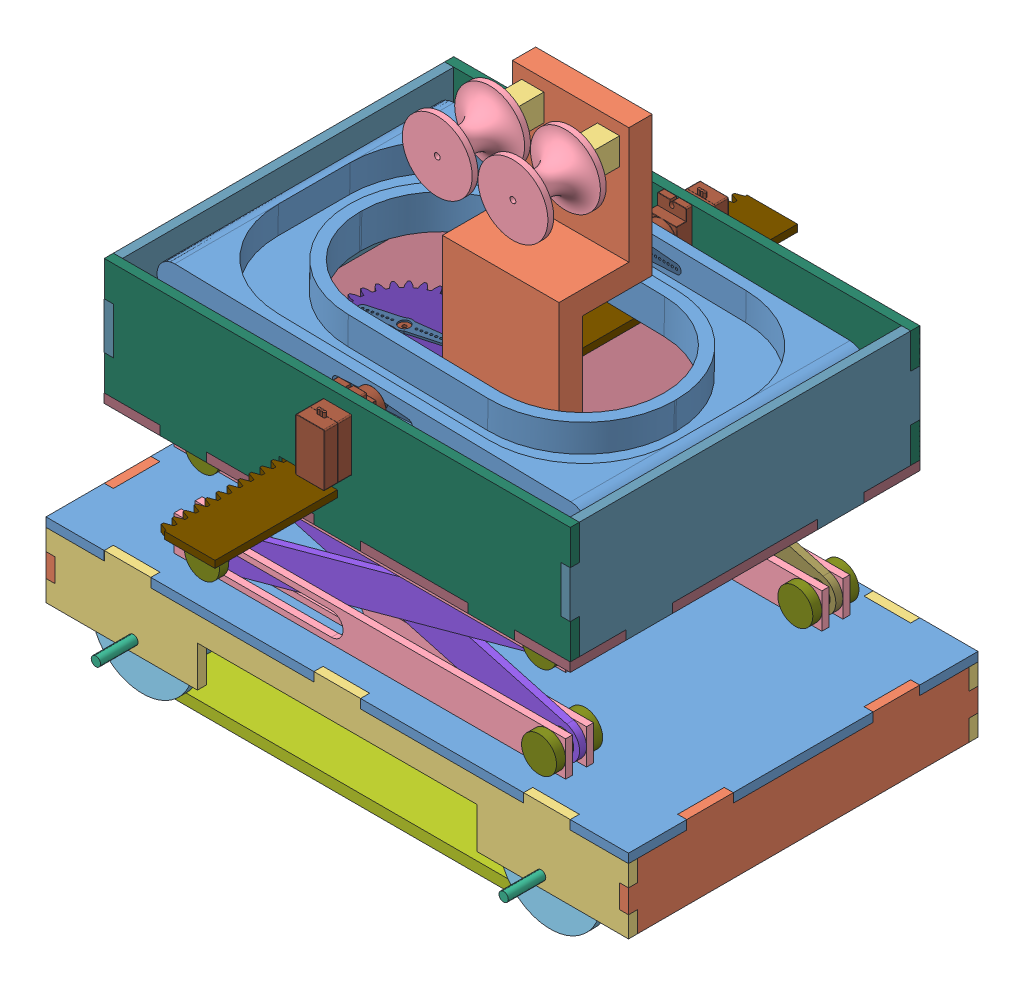
SolidWorks assembly Robot Assembly, configuration Default. Lengths in mm.
Overall size (250 228.82 250).
57 component instances, 22 part files, 82 mates.
Components (placement in the parent):
- Baseplate Assembly-1: Baseplate Assembly [Default] at (17.3063 15.6538 -16.3703) size (250 46.9 150)
  - Baseplate-1: Baseplate [Default] at (65.4966 128.7181 206.065) size (250 3.9 150)
  - Baseplate Short Side-1: Baseplate Short Side [Default] at (186.5966 114.7181 206.065) x (0 0 -1) z (0 -1 0) size (150 3.9 31.9)
  - Baseplate Wide Side-1: Baseplate Wide Side [Default] at (65.4966 114.7181 281.065) x (-1 0 0) z (0 -1 0) size (250 3.9 31.9)
  - Lift Axle Track-1: Lift Axle Track [Default] at (149.4966 132.6181 267.065) x (-1 0 0) z (0 -1 0) size (168 3 18.9)
  - Baseplate Short Side-2: Baseplate Short Side [Default] at (-55.6034 114.7181 206.065) x (0 0 1) z (0 -1 0) size (150 3.9 31.9)
  - Baseplate Wide Side-2: Baseplate Wide Side [Default] at (65.4966 114.7181 134.965) x (-1 0 0) z (0 -1 0) size (250 3.9 31.9)
  - Lift Axle Track-2: Lift Axle Track [Default] at (149.4966 132.6181 157.065) x (-1 0 0) z (0 -1 0) size (168 3 18.9)
  - Lift Axle Track-3: Lift Axle Track [Default] at (149.4966 132.6181 258.065) x (-1 0 0) z (0 -1 0) size (168 3 18.9)
  - Lift Axle Track-4: Lift Axle Track [Default] at (149.4966 132.6181 148.065) x (-1 0 0) z (0 -1 0) size (168 3 18.9)
- Wheel Assembly-4: Wheel Assembly [Default] at (-9.3855 251.3291 -27.7634) x (-1 0 0) z (0 0 1) size (227.01 52.01 182.2)
  - Wheel-1: Wheel [Default] at (-179.6884 129.9573 230.5581) x (0 0 -1) z (0.97923 0.202752 0) size (58 44 44)
  - Wheel-2: Wheel [Default] at (-179.6884 129.9573 146.3581) x (0 0 -1) z (1 0 0) size (58 44 44)
  - Wheel Axle-4: Wheel Axle [Default] at (-179.6884 129.9573 126.3581) size (4 4 182.2)
  - Treads-1: Treads [Default] at (-92.1884 129.9573 234.1581) size (216.4 41.4 50.8)
  - Treads-2: Treads [Default] at (-92.1884 129.9573 149.9581) size (216.4 41.4 50.8)
  - Wheel Axle-5: Wheel Axle [Default] at (-4.6884 129.9573 126.3581) size (4 4 182.2)
  - Wheel-3: Wheel [Default] at (-4.6884 129.9573 146.3581) x (0 0 -1) z (1 0 0) size (58 44 44)
  - Wheel-4: Wheel [Default] at (-4.6884 129.9573 230.5581) x (0 0 -1) z (0.97923 0.202752 0) size (58 44 44)
- Lift Arm-1: Lift Arm [Default] at (86.9724 175.6036 241.6947) x (0.964407 -0.264424 0) z (0 0 1) size (165 15 3)
- Lift Arm-2: Lift Arm [Default] at (86.9724 175.6036 244.6947) x (0.964407 0.264424 0) z (0 0 1) size (165 15 3)
- Servo Lift Arm - Inner-1: Servo Lift Arm - Inner [Default] at (86.9724 175.6036 134.6947) x (0.964407 0.264424 0) z (0 0 1) size (165 15 3)
- microservoArm-1: microservoArm [A2] at (86.9724 175.6036 137.6947) x (-0.964407 -0.264424 0) z (0.264424 -0.964407 0) size (34.4 3.9 7)
- microservoSG90-1: microservoSG90 [Default] at (82.0539 176.9522 106.3947) x (-0.964407 0.264424 0) z (0.264424 0.964407 0) size (32.3 29.8 12.5)
- Servo Lift Arm - Outer-1: Servo Lift Arm - Outer [Default] at (86.9724 175.6036 131.6947) x (0.964407 -0.264424 0) z (0 0 1) size (165 15 3)
- Chassis Assembly-1: Chassis Assembly [Default] at (-29.3162 88.7152 -3.3164) size (200 68.9 150)
  - Chassis Base-1: Chassis Base [Default] at (112.1191 114.2201 193.0111) size (200 3.9 150)
  - Chassis Short Side-1: Chassis Short Side [Default] at (208.2191 143.1201 193.0111) x (0 0 -1) z (0 -1 0) size (150 3.9 53.9)
  - Chassis Short Side-2: Chassis Short Side [Default] at (12.1191 143.1201 193.0111) x (0 0 -1) z (0 -1 0) size (150 3.9 53.9)
  - Lift Axle Track-1: Lift Axle Track [Default] at (196.1191 114.2201 251.0111) x (-1 0 0) z (0 1 0) size (168 3 18.9)
  - Lift Axle Track-2: Lift Axle Track [Default] at (196.1191 114.2201 141.0111) x (-1 0 0) z (0 1 0) size (168 3 18.9)
  - Lift Axle Track-3: Lift Axle Track [Default] at (196.1191 114.2201 132.0111) x (-1 0 0) z (0 1 0) size (168 3 18.9)
  - Lift Axle Track-4: Lift Axle Track [Default] at (196.1191 114.2201 242.0111) x (-1 0 0) z (0 1 0) size (168 3 18.9)
  - Chassis Wide Side-1: Chassis Wide Side [Default] at (112.1191 143.1201 121.9111) x (1 0 0) z (0 1 0) size (200 3.9 53.9)
  - Chassis Wide Side-2: Chassis Wide Side [Default] at (112.1191 143.1201 268.0111) x (1 0 0) z (0 1 0) size (200 3.9 53.9)
- microservoSG90-3: microservoSG90 [Default] at (82.8029 240.5354 276.3947) x (0 -1 0) z (1 0 0) size (32.3 29.8 12.5)
- microservoSG90-4: microservoSG90 [Default] at (31.5029 191.2354 189.6947) x (-1 0 0) z (0 0 -1) size (32.3 29.8 12.5)
- microservoArm-3: microservoArm [A2] at (36.6029 221.7354 189.6947) x (-0.980053 0 0.198735) z (0.198735 0 0.980053) size (34.4 3.9 7)
- microservoArm-5: microservoArm [A2] at (82.8029 245.6354 245.0947) x (-0.999797 0.020157 0) z (0.020157 0.999797 0) size (34.4 3.9 7)
- Lift Axle-1: Lift Axle [Default] at (159.3029 155.7718 124.7947) size (15 15 19.8)
- Lift Axle-2: Lift Axle [Default] at (159.3029 195.4354 124.7947) size (15 15 19.8)
- Lift Axle-3: Lift Axle [Default] at (159.3029 195.4354 234.7947) size (15 15 19.8)
- Lift Axle-4: Lift Axle [Default] at (159.3029 155.7718 234.7947) size (15 15 19.8)
- Lift Axle-5: Lift Axle [Default] at (14.6419 155.7718 234.7947) size (15 15 19.8)
- Lift Axle-6: Lift Axle [Default] at (14.6419 195.4354 234.7947) size (15 15 19.8)
- Lift Axle-7: Lift Axle [Default] at (14.6419 195.4354 124.7947) size (15 15 19.8)
- Lift Axle-8: Lift Axle [Default] at (14.6419 155.7718 124.7947) size (15 15 19.8)
- Servo Gear-5: Servo Gear [Servo] at (36.6029 217.8354 189.6947) x (0 1 0) z (-0.980053 0 0.198735) size (3 47.82 48)
- Spur Rack-1: Spur Rack [Metric - Rack-spur - rectangular 1.5M 20PA 5FW 15PH 250L---SAll] at (82.8029 220.8354 317.1618) x (0 0 -1) z (0 1 0) size (250 25 3)
- Balance-1: Balance [Full Trough] at (82.8029 245.6354 249.5947) x (-0.999797 0.020157 0) z (-0.020157 -0.999797 0) size (185 119.8 15)
- microservoArm-6: microservoArm [A2] at (82.8029 245.6354 134.2947) x (-0.999797 0.020157 0) z (-0.020157 -0.999797 0) size (34.4 3.9 7)
- microservoSG90-5: microservoSG90 [Default] at (82.8029 240.5354 102.9947) x (0 -1 0) z (-1 0 0) size (32.3 29.8 12.5)
- Pulley Arm-2: Pulley Arm [Default] at (107.8029 207.8354 184.5355) x (0 0 1) z (-1 0 0) size (40 110 50)
- DC Motor-1: DC Motor [Default] at (99.0529 307.0854 179.5355) x (0 0 1) z (-1 0 0) size (35 11.5 9.5)
- Pulley-2: Pulley [Default] at (99.0529 307.0854 193.0355) x (0 0 1) z (-0.996374 0.085079 0) size (25 30 30)
- Pulley-4: Pulley [Default] at (66.5529 307.0854 193.0355) x (0 0 1) z (-0.988439 0.151617 0) size (25 30 30)
- DC Motor-2: DC Motor [Default] at (66.5529 307.0854 179.5355) x (0 0 1) z (-1 0 0) size (35 11.5 9.5)
Mates (geometry in assembly coordinates):
- Concentric5: concentric anti-aligned: cylinder of Baseplate Assembly-1/Baseplate Wide Side-2 through (170.3029 121.3718 114.6947) axis (0 0 1) radius 2; cylinder of Wheel Assembly-4/Wheel Axle-4 through (170.3029 121.3718 280.7947) axis (0 0 -1) radius 2
- Coincident13: coincident anti-aligned: plane of Baseplate Assembly-1/Lift Axle Track-1 through (166.8029 148.2718 247.6947) normal (0 0 -1); plane of Lift Arm-2 through (159.3029 195.4354 247.6947) normal (0 0 1)
- Coincident14: coincident anti-aligned: plane of Baseplate Assembly-1/Lift Axle Track-3 through (166.8029 148.2718 241.6947) normal (0 0 1); plane of Lift Arm-1 through (159.3029 155.7718 241.6947) normal (0 0 -1)
- Concentric21: concentric anti-aligned: cylinder of Servo Lift Arm - Inner-1 through (86.9724 175.6036 137.6947) axis (0 0 -1) radius 3.5; cylinder of microservoArm-1 through (86.9724 175.6036 133.7947) axis (0 0 1) radius 3.5
- Coincident19: coincident anti-aligned: plane of Baseplate Assembly-1/Lift Axle Track-2 through (166.8029 148.2718 137.6947) normal (0 0 -1); plane of Servo Lift Arm - Inner-1 through (159.3029 195.4354 137.6947) normal (0 0 1)
- Coincident25: coincident anti-aligned: plane of Baseplate Assembly-1/Lift Axle Track-4 through (166.8029 148.2718 131.6947) normal (0 0 1); plane of Servo Lift Arm - Outer-1 through (159.3029 155.7718 131.6947) normal (0 0 -1)
- Coincident26: coincident anti-aligned: plane of microservoSG90-1 through (91.3123 167.9849 128.6947) normal (0.964407 -0.264424 0); plane of Servo Lift Arm - Outer-1 through (94.5911 179.9435 134.6947) normal (-0.964407 0.264424 0)
- Coincident27: coincident anti-aligned: plane of microservoSG90-1 through (94.5911 179.9435 121.9947) normal (0.264424 0.964407 0); plane of Servo Lift Arm - Outer-1 through (72.7955 185.9195 134.6947) normal (-0.264424 -0.964407 0)
- Coincident33: coincident anti-aligned: plane of Servo Lift Arm - Inner-1 through (159.3029 195.4354 137.6947) normal (0 0 1); plane of Chassis Assembly-1/Lift Axle Track-2 through (166.8029 202.9354 137.6947) normal (0 0 -1)
- Coincident43: coincident anti-aligned: plane of Chassis Assembly-1/Chassis Wide Side-2 through (82.8029 231.8354 260.7947) normal (0 0 -1); plane of microservoSG90-3 through (82.8029 240.5354 260.7947) normal (0 0 1)
- Coincident47: coincident anti-aligned: plane of Chassis Assembly-1/Chassis Base-1 through (82.8029 206.8354 189.6947) normal (0 1 0); plane of microservoSG90-4 through (31.5029 206.8354 189.6947) normal (0 -1 0)
- Concentric35: concentric anti-aligned: cylinder of microservoSG90-4 through (36.6029 221.0354 189.6947) axis (0 -1 0) radius 2.45; cylinder of microservoArm-3 through (36.6029 217.8354 189.6947) axis (0 1 0) radius 2.45
- Coincident61: coincident anti-aligned: plane of microservoArm-1 through (86.9724 175.6036 136.1947) normal (0 0 -1); plane of microservoSG90-1 through (86.9724 175.6036 136.1947) normal (0 0 1)
- Concentric38: concentric anti-aligned: cylinder of microservoArm-1 through (86.9724 175.6036 136.6947) axis (0 0 1) radius 2.35; cylinder of microservoSG90-1 through (86.9724 175.6036 136.1947) axis (0 0 -1) radius 2.45
- Concentric39: concentric anti-aligned: cylinder of Servo Lift Arm - Inner-1 through (101.6314 179.6228 137.6947) axis (0 0 -1) radius 2; cylinder of microservoArm-1 through (101.6314 179.6228 136.2947) axis (0 0 1) radius 2
- Coincident62: coincident anti-aligned: plane of microservoSG90-4 through (30.8529 217.8354 189.6947) normal (0 1 0); plane of microservoArm-3 through (36.6029 217.8354 189.6947) normal (0 -1 0)
- Concentric43: concentric anti-aligned: cylinder of microservoSG90-3 through (82.8029 245.6354 246.5947) axis (0 0 1) radius 2.45; cylinder of microservoArm-5 through (82.8029 245.6354 248.9947) axis (0 0 -1) radius 2.45
- Coincident66: coincident anti-aligned: plane of microservoSG90-3 through (82.8029 245.6354 246.5947) normal (0 0 -1); plane of microservoArm-5 through (82.8029 245.6354 246.5947) normal (0 0 1)
- LimitDistance4: limit distance = 54.6635 mm anti-aligned: plane of Baseplate Assembly-1/Baseplate-1 through (82.8029 148.2718 189.6947) normal (0 1 0); plane of Chassis Assembly-1/Chassis Base-1 through (82.8029 202.9354 189.6947) normal (0 -1 0)
- Concentric73: concentric aligned: cylinder of Servo Lift Arm - Inner-1 through (14.6419 155.7718 137.6947) axis (0 0 -1) radius 5; cylinder of Lift Axle-8 through (14.6419 155.7718 165.8079) axis (0 0 -1) radius 5
- Tangent1: tangent anti-aligned: plane of Baseplate Assembly-1/Lift Axle Track-4 through (6.3029 150.7718 128.6947) normal (0 1 0); cylinder of Lift Axle-8 through (14.6419 155.7718 165.8079) axis (0 0 -1) radius 5
- Coincident121: coincident anti-aligned: plane of Baseplate Assembly-1/Lift Axle Track-4 through (166.8029 148.2718 128.6947) normal (0 0 -1); plane of Lift Axle-8 through (14.6419 155.7718 128.6947) normal (0 0 1)
- Concentric74: concentric aligned: cylinder of Lift Arm-2 through (14.6419 155.7718 247.6947) axis (0 0 -1) radius 5; cylinder of Lift Axle-5 through (14.6419 155.7718 275.8079) axis (0 0 -1) radius 5
- Tangent2: tangent anti-aligned: plane of Baseplate Assembly-1/Lift Axle Track-1 through (6.3029 150.7718 247.6947) normal (0 1 0); cylinder of Lift Axle-5 through (14.6419 155.7718 275.8079) axis (0 0 -1) radius 5
- Coincident122: coincident anti-aligned: plane of Baseplate Assembly-1/Lift Axle Track-3 through (166.8029 148.2718 238.6947) normal (0 0 -1); plane of Lift Axle-5 through (14.6419 155.7718 238.6947) normal (0 0 1)
- Concentric75: concentric aligned: cylinder of Servo Lift Arm - Outer-1 through (14.6419 195.4354 134.6947) axis (0 0 -1) radius 5; cylinder of Lift Axle-7 through (14.6419 195.4354 165.8079) axis (0 0 -1) radius 5
- Tangent3: tangent anti-aligned: plane of Chassis Assembly-1/Lift Axle Track-2 through (6.3029 190.4354 140.6947) normal (0 1 0); cylinder of Lift Axle-7 through (14.6419 195.4354 165.8079) axis (0 0 -1) radius 5
- Coincident123: coincident anti-aligned: plane of Chassis Assembly-1/Lift Axle Track-3 through (166.8029 202.9354 128.6947) normal (0 0 -1); plane of Lift Axle-7 through (14.6419 195.4354 128.6947) normal (0 0 1)
- Concentric76: concentric aligned: cylinder of Lift Arm-1 through (14.6419 195.4354 244.6947) axis (0 0 -1) radius 5; cylinder of Lift Axle-6 through (14.6419 195.4354 275.8079) axis (0 0 -1) radius 5
- Tangent4: tangent anti-aligned: plane of Chassis Assembly-1/Lift Axle Track-1 through (6.3029 190.4354 250.6947) normal (0 1 0); cylinder of Lift Axle-6 through (14.6419 195.4354 275.8079) axis (0 0 -1) radius 5
- Coincident124: coincident anti-aligned: plane of Chassis Assembly-1/Lift Axle Track-4 through (166.8029 202.9354 238.6947) normal (0 0 -1); plane of Lift Axle-6 through (14.6419 195.4354 238.6947) normal (0 0 1)
- Concentric77: concentric anti-aligned: cylinder of Baseplate Assembly-1/Lift Axle Track-4 through (159.3029 155.7718 128.6947) axis (0 0 1) radius 5; cylinder of Lift Axle-1 through (159.3029 155.7718 165.8079) axis (0 0 -1) radius 5
- Coincident125: coincident anti-aligned: plane of Baseplate Assembly-1/Lift Axle Track-4 through (166.8029 148.2718 128.6947) normal (0 0 -1); plane of Lift Axle-1 through (159.3029 155.7718 128.6947) normal (0 0 1)
- Concentric79: concentric aligned: cylinder of Chassis Assembly-1/Lift Axle Track-3 through (159.3029 195.4354 131.6947) axis (0 0 -1) radius 5; cylinder of Lift Axle-2 through (159.3029 195.4354 165.8079) axis (0 0 -1) radius 5
- Coincident126: coincident anti-aligned: plane of Chassis Assembly-1/Lift Axle Track-3 through (166.8029 202.9354 128.6947) normal (0 0 -1); plane of Lift Axle-2 through (159.3029 195.4354 128.6947) normal (0 0 1)
- Concentric80: concentric anti-aligned: cylinder of Baseplate Assembly-1/Lift Axle Track-1 through (159.3029 155.7718 247.6947) axis (0 0 1) radius 5; cylinder of Lift Axle-4 through (159.3029 155.7718 275.8079) axis (0 0 -1) radius 5
- Coincident127: coincident anti-aligned: plane of Baseplate Assembly-1/Lift Axle Track-1 through (166.8029 148.2718 250.6947) normal (0 0 1); plane of Lift Axle-4 through (159.3029 155.7718 250.6947) normal (0 0 -1)
- Concentric81: concentric aligned: cylinder of Chassis Assembly-1/Lift Axle Track-4 through (159.3029 195.4354 241.6947) axis (0 0 -1) radius 5; cylinder of Lift Axle-3 through (159.3029 195.4354 275.8079) axis (0 0 -1) radius 5
- Coincident128: coincident anti-aligned: plane of Chassis Assembly-1/Lift Axle Track-4 through (166.8029 202.9354 238.6947) normal (0 0 -1); plane of Lift Axle-3 through (159.3029 195.4354 238.6947) normal (0 0 1)
- Concentric82: concentric anti-aligned: cylinder of microservoArm-3 through (36.6029 217.8354 189.6947) axis (0 1 0) radius 3.5; cylinder of Servo Gear-5 through (36.6029 220.8354 189.6947) axis (0 -1 0) radius 3.5
- Concentric83: concentric anti-aligned: cylinder of microservoArm-3 through (51.4997 220.3354 186.6739) axis (0 1 0) radius 2; cylinder of Servo Gear-5 through (51.4997 220.8354 186.6739) axis (0 -1 0) radius 2
- Coincident129: coincident anti-aligned: plane of microservoSG90-4 through (30.8529 217.8354 189.6947) normal (0 1 0); plane of Servo Gear-5 through (36.6029 217.8354 189.6947) normal (0 -1 0)
- Concentric87: concentric aligned: cylinder of Lift Arm-2 through (159.3029 195.4354 247.6947) axis (0 0 -1) radius 5; cylinder of Lift Axle-3 through (159.3029 195.4354 275.8079) axis (0 0 -1) radius 5
- Concentric88: concentric aligned: cylinder of Lift Arm-1 through (159.3029 155.7718 244.6947) axis (0 0 -1) radius 5; cylinder of Lift Axle-4 through (159.3029 155.7718 275.8079) axis (0 0 -1) radius 5
- Concentric89: concentric aligned: cylinder of Servo Lift Arm - Outer-1 through (159.3029 155.7718 134.6947) axis (0 0 -1) radius 5; cylinder of Lift Axle-1 through (159.3029 155.7718 165.8079) axis (0 0 -1) radius 5
- Concentric90: concentric aligned: cylinder of Servo Lift Arm - Inner-1 through (159.3029 195.4354 137.6947) axis (0 0 -1) radius 5; cylinder of Lift Axle-2 through (159.3029 195.4354 165.8079) axis (0 0 -1) radius 5
- Concentric99: concentric anti-aligned: cylinder of Baseplate Assembly-1/Baseplate Wide Side-2 through (-4.6971 121.3718 114.6947) axis (0 0 1) radius 2; cylinder of Wheel Assembly-4/Wheel Axle-5 through (-4.6971 121.3718 280.7947) axis (0 0 -1) radius 2
- Coincident137: coincident anti-aligned: plane of Baseplate Assembly-1/Baseplate Wide Side-2 through (82.8029 130.3718 118.5947) normal (0 0 1); plane of Wheel Assembly-4/Wheel-3 through (-4.6971 121.3718 118.5947) normal (0 0 -1)
- Coincident138: coincident aligned: plane of Servo Lift Arm - Inner-1 through (159.3029 195.4354 137.6947) normal (0 0 1); plane of microservoArm-1 through (101.6314 179.6228 137.6947) normal (0 0 1)
- Coincident142: coincident anti-aligned: plane of Chassis Assembly-1/Chassis Wide Side-1 through (82.8029 220.8354 114.6947) normal (0 -1 0); plane of Spur Rack-1 through (57.8029 220.8354 317.1618) normal (0 1 0)
- Coincident144: coincident anti-aligned: plane of Chassis Assembly-1/Chassis Base-1 through (42.8029 206.8354 183.4947) normal (-1 0 0); plane of microservoSG90-4 through (42.8029 206.8354 183.4947) normal (1 0 0)
- Coincident145: coincident anti-aligned: plane of Chassis Assembly-1/Chassis Base-1 through (20.2029 206.8354 183.4947) normal (0 0 1); plane of microservoSG90-4 through (42.8029 206.8354 183.4947) normal (0 0 -1)
- Coincident146: coincident anti-aligned: plane of Chassis Assembly-1/Chassis Wide Side-2 through (82.8029 231.8354 260.7947) normal (-1 0 0); plane of Spur Rack-1 through (82.8029 217.8354 317.1618) normal (1 0 0)
- Coincident147: coincident anti-aligned: plane of Chassis Assembly-1/Chassis Wide Side-2 through (89.0029 231.8354 260.7947) normal (-1 0 0); plane of microservoSG90-3 through (89.0029 251.8354 260.7947) normal (1 0 0)
- Coincident148: coincident anti-aligned: plane of Chassis Assembly-1/Chassis Wide Side-2 through (82.8029 229.2354 260.7947) normal (0 1 0); plane of microservoSG90-3 through (89.0029 229.2354 260.7947) normal (0 -1 0)
- Coincident149: coincident aligned: plane of microservoArm-5 through (97.9998 245.329 245.0947) normal (0 0 -1); plane of Balance-1 through (37.7213 242.0433 245.0947) normal (0 0 -1)
- Concentric100: concentric anti-aligned: cylinder of microservoArm-5 through (82.8029 245.6354 248.9947) axis (0 0 -1) radius 3.5; cylinder of Balance-1 through (82.8029 245.6354 209.9897) axis (0 0 1) radius 3.5
- Concentric101: concentric anti-aligned: cylinder of microservoArm-5 through (97.9998 245.329 246.4947) axis (0 0 -1) radius 2; cylinder of Balance-1 through (97.9998 245.329 209.9897) axis (0 0 1) radius 2
- Concentric104: concentric anti-aligned: cylinder of microservoArm-6 through (82.8029 245.6354 130.3947) axis (0 0 1) radius 2.45; cylinder of microservoSG90-5 through (82.8029 245.6354 132.7947) axis (0 0 -1) radius 2.45
- Coincident152: coincident anti-aligned: plane of microservoArm-6 through (82.8029 245.6354 132.7947) normal (0 0 -1); plane of microservoSG90-5 through (82.8029 245.6354 132.7947) normal (0 0 1)
- Coincident153: coincident anti-aligned: plane of Chassis Assembly-1/Chassis Wide Side-1 through (82.8029 231.8354 118.5947) normal (0 0 1); plane of microservoSG90-5 through (82.8029 240.5354 118.5947) normal (0 0 -1)
- Coincident156: coincident anti-aligned: plane of Chassis Assembly-1/Chassis Wide Side-1 through (82.8029 251.8354 114.6947) normal (0 -1 0); plane of microservoSG90-5 through (76.6029 251.8354 118.5947) normal (0 1 0)
- Coincident157: coincident anti-aligned: plane of Chassis Assembly-1/Chassis Wide Side-1 through (89.0029 231.8354 114.6947) normal (-1 0 0); plane of microservoSG90-5 through (89.0029 251.8354 118.5947) normal (1 0 0)
- Concentric105: concentric aligned: cylinder of Balance-1 through (97.9998 245.329 94.6897) axis (0 0 1) radius 2; cylinder of microservoArm-6 through (97.9998 245.329 132.8947) axis (0 0 1) radius 2
- Coincident160: coincident anti-aligned: plane of Spur Rack-1 through (82.8029 217.8354 317.1618) normal (1 0 0); plane of Pulley Arm-2 through (82.8029 217.8354 154.5355) normal (-1 0 0)
- Coincident161: coincident anti-aligned: plane of Spur Rack-1 through (57.8029 217.8354 317.1618) normal (0 -1 0); plane of Pulley Arm-2 through (57.8029 217.8354 154.5355) normal (0 1 0)
- Coincident162: coincident anti-aligned: plane of Pulley Arm-2 through (94.3029 312.8354 154.5355) normal (1 0 0); plane of DC Motor-1 through (94.3029 312.8354 154.5355) normal (-1 0 0)
- Coincident163: coincident anti-aligned: plane of Pulley Arm-2 through (94.3029 312.8354 154.5355) normal (0 -1 0); plane of DC Motor-1 through (103.8029 312.8354 154.5355) normal (0 1 0)
- Coincident164: coincident aligned: plane of Pulley Arm-2 through (57.8029 207.8354 154.5355) normal (0 0 -1); plane of DC Motor-1 through (99.0529 307.0854 154.5355) normal (0 0 -1)
- Concentric106: concentric anti-aligned: cylinder of DC Motor-1 through (99.0529 307.0854 189.5355) axis (0 0 -1) radius 1.25; cylinder of Pulley-2 through (99.0529 307.0854 180.5355) axis (0 0 1) radius 1.25
- Distance1: distance = 1 mm anti-aligned: plane of Pulley-2 through (99.0529 307.0854 180.5355) normal (0 0 -1); plane of DC Motor-1 through (99.0529 307.0854 179.5355) normal (0 0 1)
- Coincident166: coincident aligned: plane of Pulley Arm-2 through (57.8029 207.8354 154.5355) normal (0 0 -1); plane of DC Motor-1 through (99.0529 307.0854 154.5355) normal (0 0 -1)
- Distance2: distance = 1 mm anti-aligned: plane of Pulley-4 through (66.5529 307.0854 180.5355) normal (0 0 -1); plane of DC Motor-2 through (66.5529 307.0854 179.5355) normal (0 0 1)
- Concentric109: concentric anti-aligned: cylinder of Pulley-4 through (66.5529 307.0854 180.5355) axis (0 0 1) radius 1.25; cylinder of DC Motor-2 through (66.5529 307.0854 189.5355) axis (0 0 -1) radius 1.25
- Coincident167: coincident anti-aligned: plane of Pulley Arm-2 through (61.8029 312.8354 154.5355) normal (1 0 0); plane of DC Motor-2 through (61.8029 312.8354 154.5355) normal (-1 0 0)
- Coincident168: coincident anti-aligned: plane of Pulley Arm-2 through (71.3029 301.3354 154.5355) normal (0 1 0); plane of DC Motor-2 through (71.3029 301.3354 154.5355) normal (0 -1 0)
- Coincident169: coincident aligned: plane of Pulley Arm-2 through (57.8029 207.8354 154.5355) normal (0 0 -1); plane of DC Motor-2 through (66.5529 307.0854 154.5355) normal (0 0 -1)
- Coincident170: coincident anti-aligned: plane of Pulley Arm-2 through (71.3029 301.3354 154.5355) normal (0 1 0); plane of DC Motor-2 through (71.3029 301.3354 154.5355) normal (0 -1 0)
- Coincident171: coincident aligned: plane of Pulley Arm-2 through (57.8029 207.8354 154.5355) normal (0 0 -1); plane of DC Motor-2 through (66.5529 307.0854 154.5355) normal (0 0 -1)
- Coincident172: coincident aligned: plane of Pulley Arm-2 through (57.8029 207.8354 154.5355) normal (0 0 -1); plane of DC Motor-2 through (66.5529 307.0854 154.5355) normal (0 0 -1)
- Coincident173: coincident aligned: plane of Pulley Arm-2 through (57.8029 207.8354 154.5355) normal (0 0 -1); plane of DC Motor-2 through (66.5529 307.0854 154.5355) normal (0 0 -1)
- Coincident174: coincident anti-aligned: plane of Pulley Arm-2 through (71.3029 312.8354 154.5355) normal (0 -1 0); plane of DC Motor-2 through (71.3029 312.8354 154.5355) normal (0 1 0)
